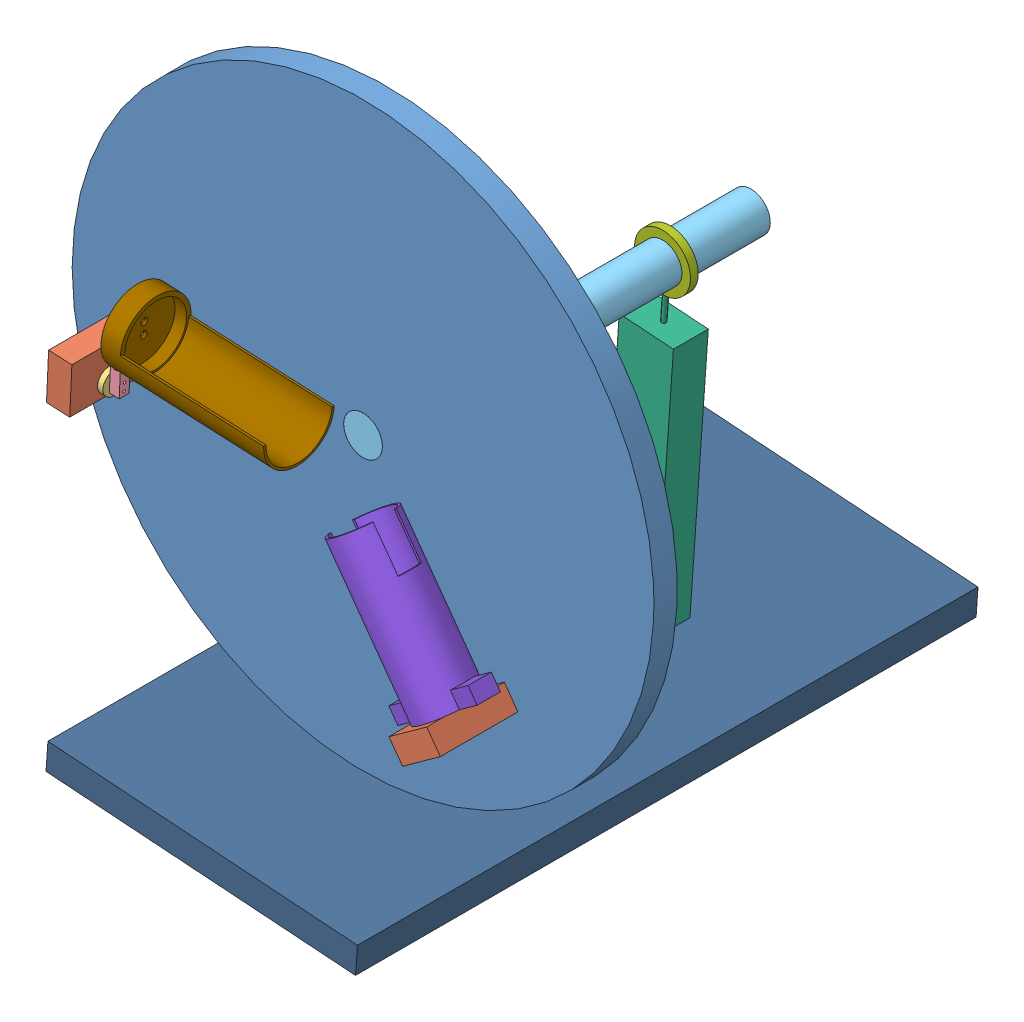
SolidWorks assembly MaschineBaugrp, configuration Standard. Lengths in mm.
Overall size (750 825.88 800).
14 component instances, 10 part files, 22 mates.
Components (placement in the parent):
- Holzplatte-1: Holzplatte [Standard] at (3.8495 -3.5533 500) size (750 750 30)
- Sensorhalter-1: Sensorhalter [Standard] at (-304.2666 -71.0723 630) x (0.046448 0.998921 0) z (0 0 -1) size (60 30 100)
- Abstandshalter-1: Abstandshalter [Standard] at (-266.4758 -54.9252 580) x (0.046448 0.998921 0) z (-0.998921 0.046448 0) size (30 30 7)
- HX711-01-1: HX711-01 [Standard] at (-263.3817 11.6179 573.65) x (-0.046448 -0.998921 0) z (0 0 1) size (75 12.7 12.7)
- Abstandshalter-2: Abstandshalter [Standard] at (-244.1304 1.5089 583.5058) x (-0.046448 -0.998921 0) z (-0.998921 0.046448 0) size (30 30 7)
- Welle-1: Welle [Standard] at (3.8495 -3.5533 30) x (-0.115446 -0.993314 0) z (0 0 1) size (50 50 500)
- Sensorhalter-2: Sensorhalter [Standard] at (203.4592 -212.5183 630) x (-0.810635 -0.585552 0) z (0 0 -1) size (60 30 100)
- Aufstand-3: Aufstand [Standard] at (-22.5339 -407.0308 430.6722) x (0.997496 -0.070716 0) z (0.070716 0.997496 0) size (70 45 370)
- Aufstand-4: Aufstand [Standard] at (-22.5339 -407.0308 139.6251) x (0.997496 -0.070716 0) z (0.070716 0.997496 0) size (70 45 370)
- Lager-1: Lager [Standard] at (3.8495 -3.5533 133.9162) x (0.999652 -0.026364 0) z (-0.026364 -0.999652 0) size (72 10 72)
- Lager-2: Lager [Standard] at (3.8495 -3.5533 434.7624) x (0.558708 -0.829364 0) z (0.829364 0.558708 0) size (72 10 72)
- Weizenflaschenhalter-1: Weizenflaschenhalter [Standard] at (158.7787 -195.4486 579.8092) x (0.810635 0.585552 0) z (-0.585552 0.810635 0) size (126 76 190)
- Weizenglashalter-1: Weizenglashalter [Standard] at (-233.2579 20.0408 575.2691) x (0.046448 0.998921 0) z (0.998921 -0.046448 0) size (91 91 210)
- Bodenplatte-1: Bodenplatte [Standard] at (-48.3434 -440.2889 287.0215) x (0.997496 -0.070716 0) z (0.070716 0.997496 0) size (400 800 35)
Mates (geometry in assembly coordinates):
- Deckungsgleich3: coincident anti-aligned: plane of Holzplatte-1 through (3.8495 -3.5533 530) normal (0 0 1); plane of Sensorhalter-1 through (-304.2666 -71.0723 530) normal (0 0 -1)
- Deckungsgleich5: coincident anti-aligned: circle of Sensorhalter-1; circle of Abstandshalter-1
- Konzentrisch3: concentric anti-aligned: circle of Abstandshalter-1; circle of HX711-01-1
- Deckungsgleich7: coincident anti-aligned: plane of Abstandshalter-1 through (-266.4758 -54.9252 580) normal (0.998921 -0.046448 0); plane of HX711-01-1 through (-263.3817 11.6179 586.35) normal (-0.998921 0.046448 0)
- Deckungsgleich8: coincident anti-aligned: plane of HX711-01-1 through (-250.6954 11.028 586.35) normal (0.998921 -0.046448 0); plane of Abstandshalter-2 through (-251.1229 1.834 583.5058) normal (-0.998921 0.046448 0)
- Deckungsgleich23: coincident anti-aligned: plane of Holzplatte-1 through (3.8495 -3.5533 530) normal (0 0 1); plane of Sensorhalter-2 through (203.4592 -212.5183 530) normal (0 0 -1)
- Konzentrisch6: concentric aligned: circle of Holzplatte-1; circle of Welle-1
- Deckungsgleich27: coincident aligned: plane of Holzplatte-1 through (3.8495 -3.5533 530) normal (0 0 1); plane of Welle-1 through (3.8495 -3.5533 530) normal (0 0 1)
- Konzentrisch7: concentric anti-aligned: circle of Welle-1; circle of Lager-2
- Konzentrisch8: concentric anti-aligned: circle of Lager-1; circle of Lager-2
- Deckungsgleich28: coincident anti-aligned: plane of Sensorhalter-2 through (185.8927 -188.1993 530) normal (-0.585552 0.810635 0); plane of Weizenflaschenhalter-1 through (164.6343 -203.555 579.8092) normal (0.585552 -0.810635 0)
- Deckungsgleich29: coincident anti-aligned: plane of Abstandshalter-2 through (-244.1304 1.5089 583.5058) normal (0.998921 -0.046448 0); plane of Weizenglashalter-1 through (-243.2471 20.5053 575.2691) normal (-0.998921 0.046448 0)
- Parallel1: parallel aligned: plane of Sensorhalter-1 through (-301.4797 -11.137 530) normal (0.046448 0.998921 0); plane of Weizenglashalter-1 through (-33.4738 10.7511 575.2691) normal (0.046448 0.998921 0)
- Parallel2: parallel aligned: plane of Aufstand-3 through (-33.7564 -70.3944 408.1722) normal (-0.997496 0.070716 0); plane of Aufstand-4 through (-33.7564 -70.3944 117.1251) normal (-0.997496 0.070716 0)
- Parallel3: parallel aligned: plane of Aufstand-3 through (-22.5339 -407.0308 430.6722) normal (-0.070716 -0.997496 0); plane of Aufstand-4 through (-22.5339 -407.0308 139.6251) normal (-0.070716 -0.997496 0)
- Parallel4: parallel aligned: plane of Sensorhalter-2 through (203.4592 -212.5183 630) normal (0 0 1); plane of Weizenflaschenhalter-1 through (164.6343 -203.555 594.8092) normal (0 0 1)
- Parallel5: parallel anti-aligned: plane of Holzplatte-1 through (3.8495 -3.5533 500) normal (0 0 -1); plane of Aufstand-3 through (-33.7564 -70.3944 453.1722) normal (0 0 1)
- Deckungsgleich36: coincident aligned: plane of Aufstand-3 through (-22.5339 -407.0308 430.6722) normal (-0.070716 -0.997496 0); plane of Aufstand-4 through (-22.5339 -407.0308 139.6251) normal (-0.070716 -0.997496 0)
- Parallel7: parallel anti-aligned: plane of Holzplatte-1 through (3.8495 -3.5533 500) normal (0 0 -1); plane of Aufstand-4 through (-33.7564 -70.3944 162.1251) normal (0 0 1)
- Deckungsgleich38: coincident aligned: plane of Aufstand-3 through (-33.7564 -70.3944 408.1722) normal (-0.997496 0.070716 0); plane of Aufstand-4 through (-33.7564 -70.3944 117.1251) normal (-0.997496 0.070716 0)
- Deckungsgleich39: coincident anti-aligned: plane of Aufstand-3 through (-22.5339 -407.0308 430.6722) normal (-0.070716 -0.997496 0); plane of Bodenplatte-1 through (-45.8684 -405.3765 287.0215) normal (0.070716 0.997496 0)
- Parallel8: parallel aligned: plane of Aufstand-3 through (36.0683 -75.3445 408.1722) normal (0.997496 -0.070716 0); plane of Bodenplatte-1 through (153.6309 -419.5197 -112.9785) normal (0.997496 -0.070716 0)
